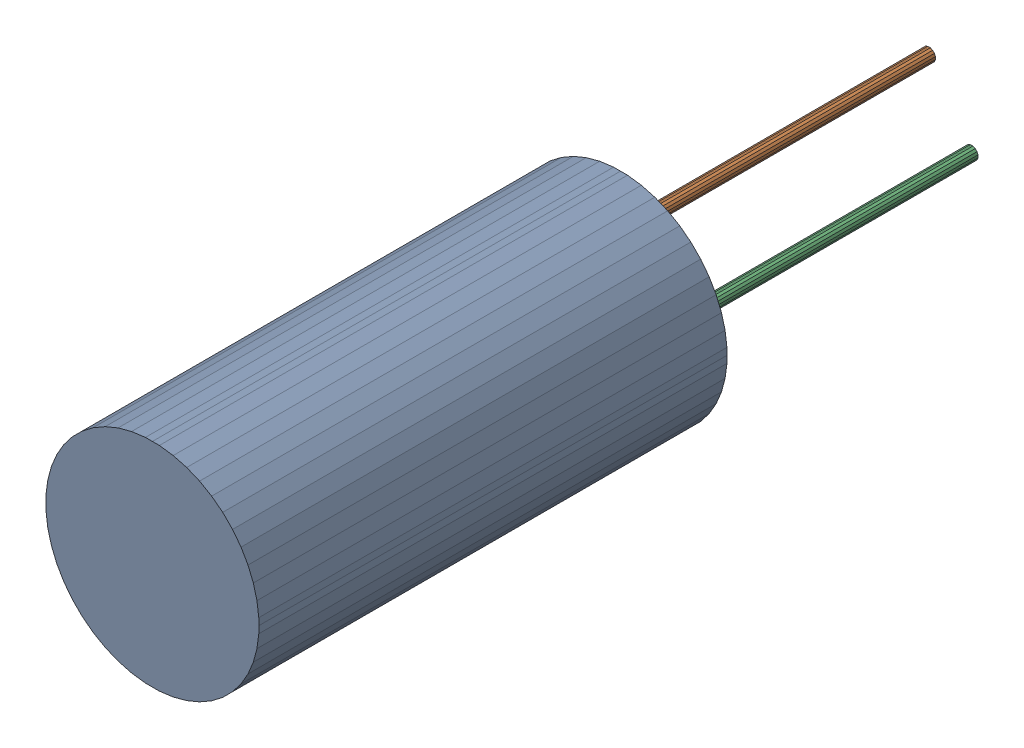
SolidWorks assembly C1.step, configuration Default. Lengths in mm.
Overall size (10 10 39).
6 component instances, 3 part files, 0 mates.
Components (placement in the parent):
- 6100340144.step-1: 6100340144.step [Default] at (44.998 49.657 0) size (10 10 22)
  - Extruded-50.step-1: Extruded-50.step [Default] at origin size (10 10 22)
- 6100332544.step-1: 6100332544.step [Default] at (42.498 49.657 -17) size (0.6 0.6 17)
  - Extruded-51.step-1: Extruded-51.step [Default] at origin size (0.6 0.6 17)
- 6100341584.step-1: 6100341584.step [Default] at (47.4979 49.6571 -14) size (0.6 0.6 14)
  - Extruded-52.step-1: Extruded-52.step [Default] at origin size (0.6 0.6 14)
